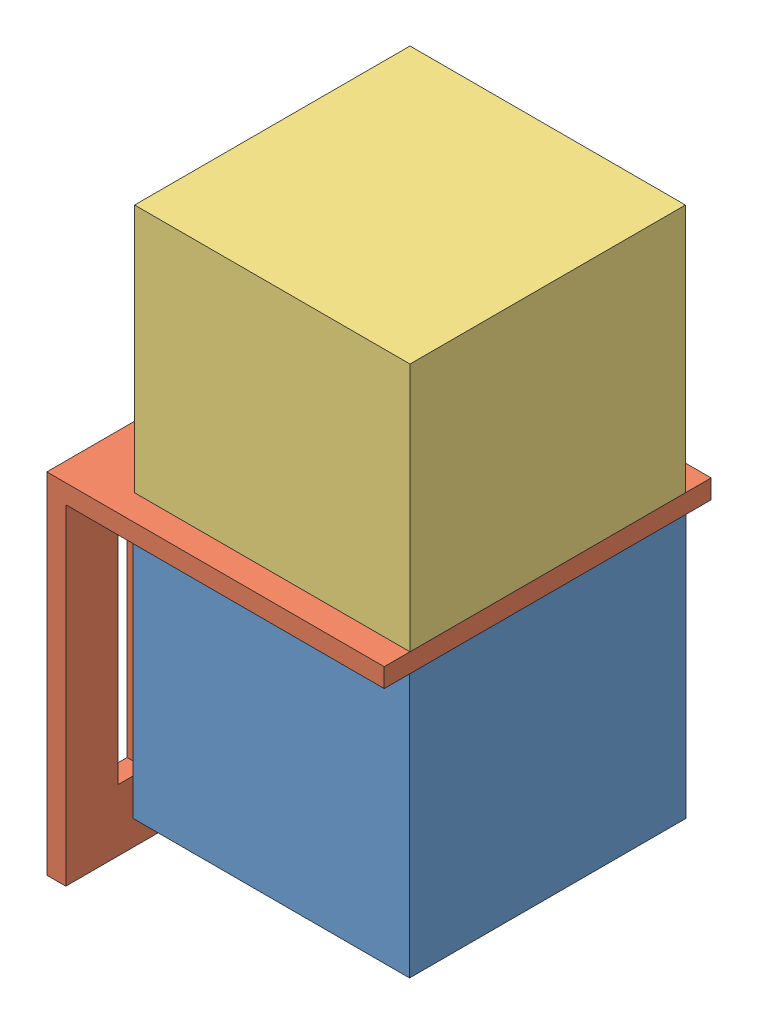
SolidWorks assembly extruderAssem, configuration Default. Lengths in mm.
Overall size (51.58 91.5 56.04).
3 component instances, 3 part files, 6 mates.
Components (placement in the parent):
- extruder-1: extruder [Default] at (-17.4789 7.2431 56.3238) size (42.24 40.25 42.24)
- motorMount-1: motorMount [Default] at (24.7611 50.3931 60.1938) x (-1 0 0) z (0 0 1) size (51.58 53.4 49.98)
- extruderNonMotorPart-1: extruderNonMotorPart [Default] at (-17.3389 50.3931 56.2538) size (42.1 38.1 52.1)
Mates (geometry in assembly coordinates):
- Coincident1: coincident: plane of extruder-1 through (-17.4789 47.4931 56.3238) normal (0 1 0); plane of motorMount-1 through (24.7611 47.4931 60.1938) normal (0 -1 0)
- Coincident2: coincident: plane of extruder-1 through (24.7611 47.4931 56.3238) normal (1 0 0); plane of motorMount-1 through (24.7611 47.4931 60.1938) normal (1 0 0)
- Width1: width anti-aligned: plane of motorMount-1 through (24.7611 47.4931 10.2138) normal (0 0 -1); plane of extruder-1 through (24.7611 47.4931 60.1938) normal (0 0 1); plane of motorMount-1 through (-17.4789 47.4931 56.3238) normal (0 0 1); plane of extruder-1 through (-17.4789 47.4931 14.0838) normal (0 0 -1)
- Coincident3: coincident anti-aligned: plane of motorMount-1 through (24.7611 50.3931 60.1938) normal (0 1 0); plane of extruderNonMotorPart-1 through (-17.3389 50.3931 56.2538) normal (0 -1 0)
- Coincident5: coincident aligned: plane of extruder-1 through (24.7611 47.4931 56.3238) normal (1 0 0); plane of extruderNonMotorPart-1 through (24.7611 88.4931 56.2538) normal (1 0 0)
- Width2: width anti-aligned: plane of extruderNonMotorPart-1 through (-17.3389 88.4931 14.1538) normal (0 0 -1); plane of motorMount-1 through (-17.3389 88.4931 56.2538) normal (0 0 1); plane of extruderNonMotorPart-1 through (24.7611 47.4931 60.1938) normal (0 0 1); plane of motorMount-1 through (24.7611 47.4931 10.2138) normal (0 0 -1)
